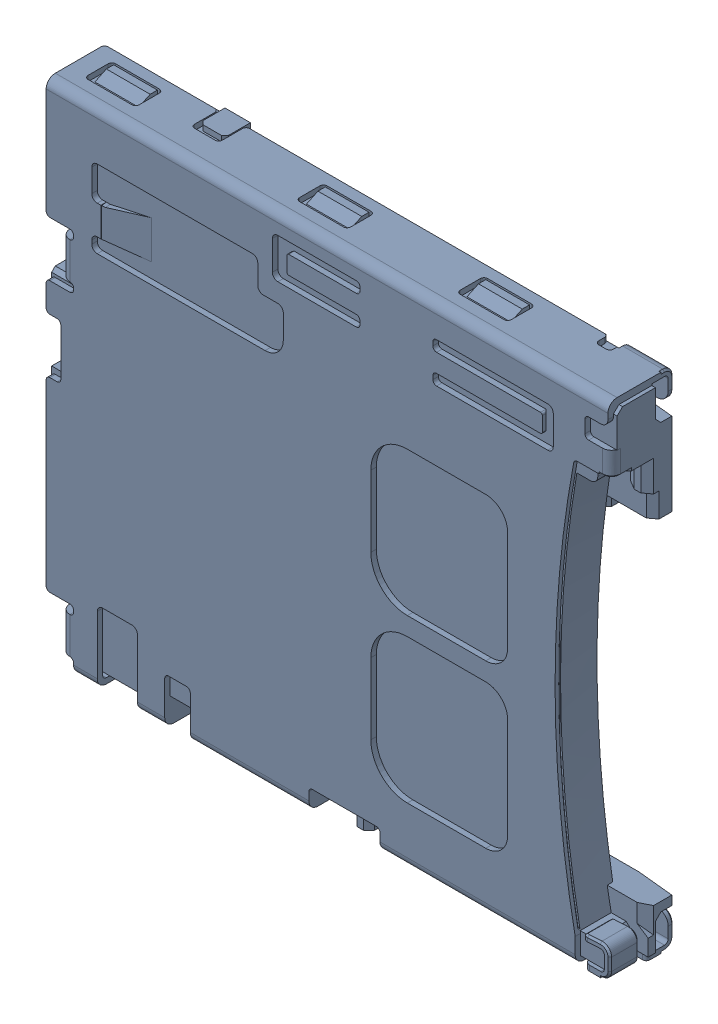
SolidWorks assembly P6, configuration Default. Lengths in mm.
Overall size (15.5 13.8 1.8).
2 component instances, 1 part files, 0 mates.
Components (placement in the parent):
- 5025700893-1: 5025700893 [Default] at (17.2345 76.9985 0.9152) x (0 -1 0) z (0 0 1) size (13.8 15.5 1.8)
  - Open CASCADE STEP translator 6.8 1.83.1.1-1: Open CASCADE STEP translator 6.8 1.83.1.1 [Default] at origin size (13.8 15.5 1.8)
